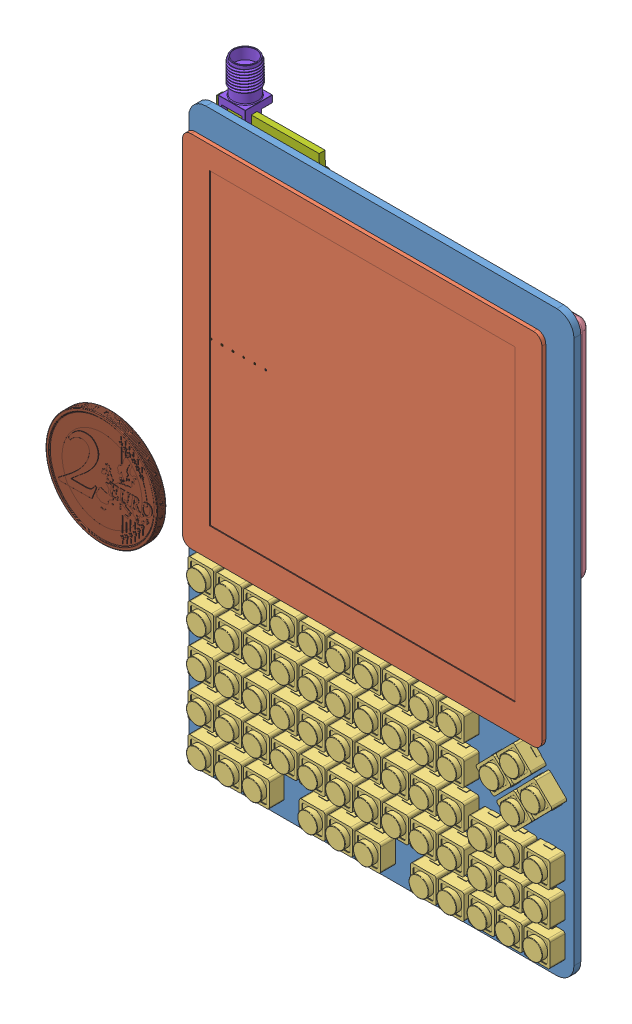
SolidWorks assembly BlaspBerry720, configuration Défaut. Lengths in mm.
Overall size (130.32 143.9 13.87).
73 component instances, 11 part files, 14 mates.
Components (placement in the parent):
- MainBoard-1: MainBoard [Défaut] at (-50.403 60.8363 134.2) size (90 136.79 1.6)
- BLOCK_Ecran-1: BLOCK_Ecran [Défaut] at (-19.3717 20.115 136.4671) x (-1 0 0) z (0 0 -1) size (84 93.34 9.7)
- ButtonTP1003-1: ButtonTP1003 [Défaut] at (-47.1009 -34.729 135.8) size (6 6.2 4.6)
- ButtonTP1003-2: ButtonTP1003 [Défaut] at (-47.1009 -43.729 135.8) size (6 6.2 4.6)
- ButtonTP1003-3: ButtonTP1003 [Défaut] at (-47.1009 -52.729 135.8) size (6 6.2 4.6)
- ButtonTP1003-4: ButtonTP1003 [Défaut] at (-47.1009 -61.729 135.8) size (6 6.2 4.6)
- ButtonTP1003-5: ButtonTP1003 [Défaut] at (-47.1009 -70.729 135.8) size (6 6.2 4.6)
- ButtonTP1003-6: ButtonTP1003 [Défaut] at (-40.6009 -34.729 135.8) size (6 6.2 4.6)
- ButtonTP1003-7: ButtonTP1003 [Défaut] at (-40.6009 -43.729 135.8) size (6 6.2 4.6)
- ButtonTP1003-8: ButtonTP1003 [Défaut] at (-40.6009 -52.729 135.8) size (6 6.2 4.6)
- ButtonTP1003-9: ButtonTP1003 [Défaut] at (-40.6009 -61.729 135.8) size (6 6.2 4.6)
- ButtonTP1003-10: ButtonTP1003 [Défaut] at (-40.6009 -70.729 135.8) size (6 6.2 4.6)
- ButtonTP1003-11: ButtonTP1003 [Défaut] at (-34.1009 -34.729 135.8) size (6 6.2 4.6)
- ButtonTP1003-12: ButtonTP1003 [Défaut] at (-34.1009 -43.729 135.8) size (6 6.2 4.6)
- ButtonTP1003-13: ButtonTP1003 [Défaut] at (-34.1009 -52.729 135.8) size (6 6.2 4.6)
- ButtonTP1003-14: ButtonTP1003 [Défaut] at (-34.1009 -61.729 135.8) size (6 6.2 4.6)
- ButtonTP1003-15: ButtonTP1003 [Défaut] at (-34.1009 -70.729 135.8) size (6 6.2 4.6)
- ButtonTP1003-16: ButtonTP1003 [Défaut] at (-27.6009 -34.729 135.8) size (6 6.2 4.6)
- ButtonTP1003-17: ButtonTP1003 [Défaut] at (-27.6009 -43.729 135.8) size (6 6.2 4.6)
- ButtonTP1003-18: ButtonTP1003 [Défaut] at (-27.6009 -52.729 135.8) size (6 6.2 4.6)
- ButtonTP1003-19: ButtonTP1003 [Défaut] at (-27.6009 -61.729 135.8) size (6 6.2 4.6)
- ButtonTP1003-21: ButtonTP1003 [Défaut] at (-21.1009 -34.729 135.8) size (6 6.2 4.6)
- ButtonTP1003-22: ButtonTP1003 [Défaut] at (-21.1009 -43.729 135.8) size (6 6.2 4.6)
- ButtonTP1003-23: ButtonTP1003 [Défaut] at (-21.1009 -52.729 135.8) size (6 6.2 4.6)
- ButtonTP1003-24: ButtonTP1003 [Défaut] at (-21.1009 -61.729 135.8) size (6 6.2 4.6)
- ButtonTP1003-25: ButtonTP1003 [Défaut] at (-21.1009 -70.729 135.8) size (6 6.2 4.6)
- ButtonTP1003-26: ButtonTP1003 [Défaut] at (-14.6009 -34.729 135.8) size (6 6.2 4.6)
- ButtonTP1003-27: ButtonTP1003 [Défaut] at (-14.6009 -43.729 135.8) size (6 6.2 4.6)
- ButtonTP1003-28: ButtonTP1003 [Défaut] at (-14.6009 -52.729 135.8) size (6 6.2 4.6)
- ButtonTP1003-29: ButtonTP1003 [Défaut] at (-14.6009 -61.729 135.8) size (6 6.2 4.6)
- ButtonTP1003-30: ButtonTP1003 [Défaut] at (-14.6009 -70.729 135.8) size (6 6.2 4.6)
- ButtonTP1003-31: ButtonTP1003 [Défaut] at (-8.1009 -34.729 135.8) size (6 6.2 4.6)
- ButtonTP1003-32: ButtonTP1003 [Défaut] at (-8.1009 -43.729 135.8) size (6 6.2 4.6)
- ButtonTP1003-33: ButtonTP1003 [Défaut] at (-8.1009 -52.729 135.8) size (6 6.2 4.6)
- ButtonTP1003-34: ButtonTP1003 [Défaut] at (-8.1009 -61.729 135.8) size (6 6.2 4.6)
- ButtonTP1003-35: ButtonTP1003 [Défaut] at (-8.1009 -70.729 135.8) size (6 6.2 4.6)
- ButtonTP1003-36: ButtonTP1003 [Défaut] at (-1.6009 -34.729 135.8) size (6 6.2 4.6)
- ButtonTP1003-37: ButtonTP1003 [Défaut] at (-1.6009 -43.729 135.8) size (6 6.2 4.6)
- ButtonTP1003-38: ButtonTP1003 [Défaut] at (-1.6009 -52.729 135.8) size (6 6.2 4.6)
- ButtonTP1003-39: ButtonTP1003 [Défaut] at (-1.6009 -61.729 135.8) size (6 6.2 4.6)
- ButtonTP1003-41: ButtonTP1003 [Défaut] at (4.8991 -34.729 135.8) size (6 6.2 4.6)
- ButtonTP1003-42: ButtonTP1003 [Défaut] at (4.8991 -43.729 135.8) size (6 6.2 4.6)
- ButtonTP1003-43: ButtonTP1003 [Défaut] at (4.8991 -52.729 135.8) size (6 6.2 4.6)
- ButtonTP1003-44: ButtonTP1003 [Défaut] at (4.8991 -61.729 135.8) size (6 6.2 4.6)
- ButtonTP1003-45: ButtonTP1003 [Défaut] at (4.8991 -70.729 135.8) size (6 6.2 4.6)
- ButtonTP1003-46: ButtonTP1003 [Défaut] at (11.3991 -34.729 135.8) size (6 6.2 4.6)
- ButtonTP1003-47: ButtonTP1003 [Défaut] at (11.3991 -43.729 135.8) size (6 6.2 4.6)
- ButtonTP1003-48: ButtonTP1003 [Défaut] at (11.3991 -52.729 135.8) size (6 6.2 4.6)
- ButtonTP1003-49: ButtonTP1003 [Défaut] at (11.3991 -61.729 135.8) size (6 6.2 4.6)
- ButtonTP1003-50: ButtonTP1003 [Défaut] at (11.3991 -70.729 135.8) size (6 6.2 4.6)
- ButtonTP1003-51: ButtonTP1003 [Défaut] at (24.7899 -32.8272 135.8) x (0.71483 -0.699299 0) z (0 0 1) size (6 6.2 4.6)
- ButtonTP1003-52: ButtonTP1003 [Défaut] at (24.3315 -41.848 135.8) x (0.699299 0.71483 0) z (0 0 1) size (6 6.2 4.6)
- ButtonTP1003-53: ButtonTP1003 [Défaut] at (33.3523 -42.3064 135.8) x (-0.71483 0.699299 0) z (0 0 1) size (6 6.2 4.6)
- ButtonTP1003-54: ButtonTP1003 [Défaut] at (33.8107 -33.2856 135.8) x (-0.699299 -0.71483 0) z (0 0 1) size (6 6.2 4.6)
- ButtonTP1003-55: ButtonTP1003 [Défaut] at (18.4794 -54.2731 135.8) size (6 6.2 4.6)
- ButtonTP1003-56: ButtonTP1003 [Défaut] at (18.4794 -62.2731 135.8) size (6 6.2 4.6)
- ButtonTP1003-57: ButtonTP1003 [Défaut] at (24.9794 -54.2731 135.8) size (6 6.2 4.6)
- ButtonTP1003-58: ButtonTP1003 [Défaut] at (24.9794 -62.2731 135.8) size (6 6.2 4.6)
- ButtonTP1003-59: ButtonTP1003 [Défaut] at (31.4794 -54.2731 135.8) size (6 6.2 4.6)
- ButtonTP1003-60: ButtonTP1003 [Défaut] at (31.4794 -62.2731 135.8) size (6 6.2 4.6)
- ButtonTP1003-61: ButtonTP1003 [Défaut] at (18.4794 -70.2731 135.8) size (6 6.2 4.6)
- ButtonTP1003-62: ButtonTP1003 [Défaut] at (24.9794 -70.2731 135.8) size (6 6.2 4.6)
- ButtonTP1003-63: ButtonTP1003 [Défaut] at (31.4794 -70.2731 135.8) size (6 6.2 4.6)
- LiPo Battery v5-1: LiPo Battery v5 [Défaut] at (6.0825 29.6693 131.51) x (1 0 0) z (0 1 0) size (71.2 5.38 53.84)
- sodimm-1: sodimm [Défaut] at (-4.7371 -7.1337 131.55) x (-1 0 0) z (0 -1 0) size (71.5 5.9 26.05)
- computeModule-1: computeModule [Défaut] at (29.1665 -3.0511 130.43) x (0 0 1) z (1 0 0) size (1 30 67.6)
- E32-TTL-1: E32-TTL [Predeterminado] at (-36.4615 105.5185 111.647) x (-0.00723 0.999974 0) z (-0.999974 -0.00723 0) size (52.5 13.63 24)
  - E32-TTL-1W-1: E32-TTL-1W [Predeterminado] at (-66.873 -19.9517 0) size (43 3.79 24)
  - SMA CONNECTOR - EMPCB.SMAFSTJ.B.HT-1: SMA CONNECTOR - EMPCB.SMAFSTJ.B.HT [Default] at (-43.773 -15.0017 10.2201) x (0 0 1) z (1 0 0) size (7.33 6.47 13.3)
  - 05_ HEADER-3WAY-1ROW-2.54MM-VERTICAL-PCB-1: 05_ HEADER-3WAY-1ROW-2.54MM-VERTICAL-PCB [Predeterminado] at (-87.6961 -24.2405 2.52) x (0 -1 0) z (0 0 1) size (11.55 2.54 7.62)
  - 05_ HEADER-3WAY-1ROW-2.54MM-VERTICAL-PCB-2: 05_ HEADER-3WAY-1ROW-2.54MM-VERTICAL-PCB [Predeterminado] at (-87.6961 -24.2405 -5.1) x (0 -1 0) z (0 0 1) size (11.55 2.54 7.62)
  - HEADER-1WAY-1ROW-2.54MM-VERTICAL-PCB-1: HEADER-1WAY-1ROW-2.54MM-VERTICAL-PCB [Predeterminado] at (-86.893 -19.9517 -7.64) x (0 -1 0) z (-1 0 0) size (11.54 2.54 2.54)
- 2euro-1: 2euro [Predeterminado] at (-77.6638 -33.7858 126.8278) x (0.999991 -0.004243 0) z (-0.004243 -0.999991 0) size (26.01 3.7 26.04)
Mates (geometry in assembly coordinates):
- Parallèle1: parallel aligned: plane of MainBoard-1 through (-46.403 -70.1637 135.8) normal (0 0 1); plane of BLOCK_Ecran-1 through (-47.4216 -26.0344 140.0671) normal (0 0 1)
- Parallèle2: parallel aligned: plane of MainBoard-1 through (-46.403 60.8363 135.8) normal (0 1 0); plane of BLOCK_Ecran-1 through (-45.4216 57.9656 139.3671) normal (0 1 0)
- Coïncidente4: coincident anti-aligned: plane of MainBoard-1 through (-46.403 -70.1637 135.8) normal (0 0 1); plane of ButtonTP1003-1 through (-41.6009 -34.229 135.8) normal (0 0 -1)
- Coïncidente5: coincident anti-aligned: plane of MainBoard-1 through (-46.403 -70.1637 135.8) normal (0 0 1); plane of ButtonTP1003-51 through (29.0711 -36.316 135.8) normal (0 0 -1)
- Coïncidente6: coincident anti-aligned: plane of MainBoard-1 through (-46.403 -70.1637 135.8) normal (0 0 1); plane of ButtonTP1003-55 through (23.9794 -53.7731 135.8) normal (0 0 -1)
- Coïncidente7: coincident anti-aligned: plane of MainBoard-1 through (-46.403 -70.1637 134.2) normal (0 0 -1); plane of LiPo Battery v5-1 through (8.4825 29.6693 134.2) normal (0 0 1)
- Parallèle3: parallel aligned: plane of MainBoard-1 through (-46.403 -74.1637 135.8) normal (0 -1 0); plane of LiPo Battery v5-1 through (36.5825 3.1693 131.51) normal (0 -1 0)
- Parallèle4: parallel aligned: plane of MainBoard-1 through (-46.403 -70.1637 134.2) normal (0 0 -1); plane of sodimm-1 through (-40.2371 -7.1337 128.95) normal (0 0 -1)
- Coïncidente10: coincident anti-aligned: plane of MainBoard-1 through (-46.403 -70.1637 134.2) normal (0 0 -1); plane of sodimm-1 through (-36.0121 -7.9337 134.2) normal (0 0 1)
- Parallèle5: parallel aligned: plane of MainBoard-1 through (-50.403 56.8363 135.8) normal (-1 0 0); plane of sodimm-1 through (-40.2371 -7.1337 132.9) normal (-1 0 0)
- Parallèle6: parallel anti-aligned: plane of MainBoard-1 through (-46.403 -70.1637 134.2) normal (0 0 -1); plane of computeModule-1 through (-4.6335 -18.0511 131.43) normal (0 0 1)
- Parallèle7: parallel anti-aligned: plane of sodimm-1 through (-37.0871 -5.2837 134.15) normal (0 -1 0); plane of computeModule-1 through (29.1665 -3.0511 130.43) normal (0 1 0)
- Coïncidente14: coincident anti-aligned: plane of sodimm-1 through (-38.6871 -7.1337 131.43) normal (0 0 -1); plane of computeModule-1 through (-4.6335 -18.0511 131.43) normal (0 0 1)
- Parallèle8: parallel aligned: plane of MainBoard-1 through (-46.403 -70.1637 134.2) normal (0 0 -1); plane of 2euro-1 through (-77.6638 -33.7858 127.0278) normal (0 0 -1)
